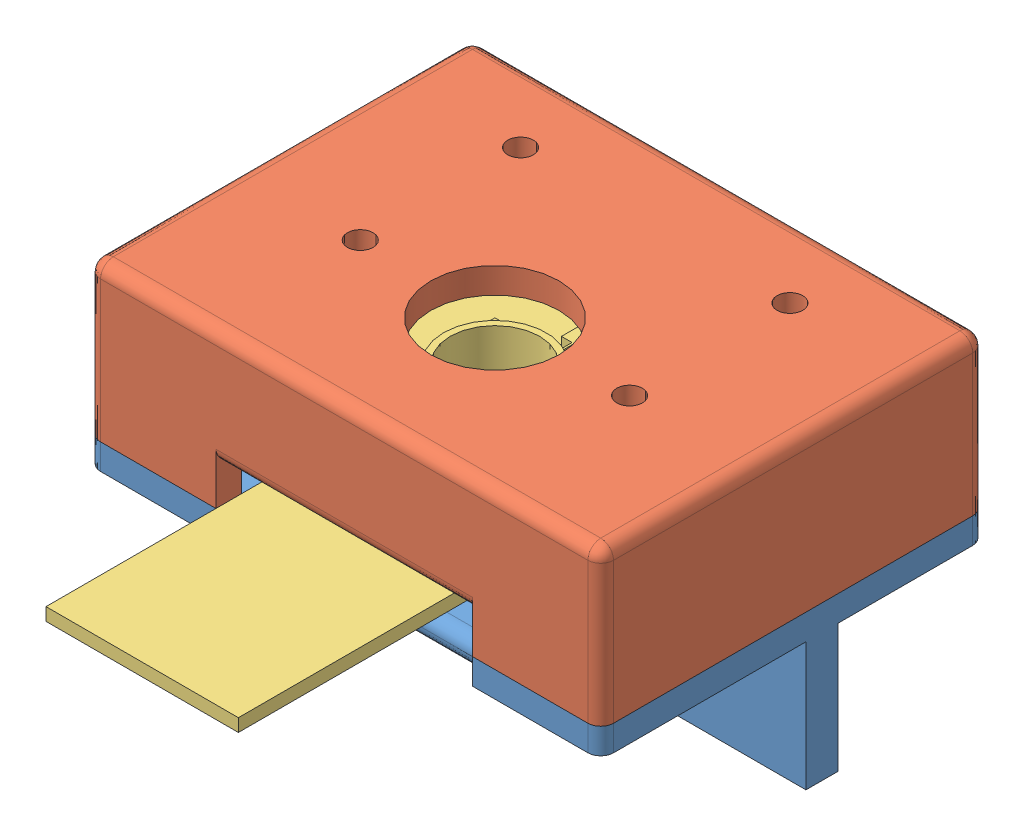
SolidWorks assembly Cam hosuing Assembly, configuration Default. Lengths in mm.
Overall size (40 24 45.75).
7 component instances, 4 part files, 8 mates.
Components (placement in the parent):
- Camera case bottomV3-1: Camera case bottomV3 [Default] at (8.7902 13.4979 31.0406) size (40 18 30)
- Camera Case Top-1: Camera Case Top [Default] at (8.7902 25.4979 31.0406) x (1 0 0) z (0 1 0) size (40 30 12)
- Raspberry Pi-1: Raspberry Pi [Default] at (8.7902 18.4979 31.7906) x (1 0 0) z (0 1 0) size (25 42 8)
- pan head tapping screw_am-1: pan head tapping screw_am [PHT 2-type I-D-10-S] at (-8.2098 12.0979 19.5406) x (0 1 0) z (0 0 1) size (11.4 4 4)
- pan head tapping screw_am-2: pan head tapping screw_am [PHT 2-type I-D-10-S] at (-8.2098 12.0979 42.5406) x (0 1 0) z (0 0 1) size (11.4 4 4)
- pan head tapping screw_am-3: pan head tapping screw_am [PHT 2-type I-D-10-S] at (25.7902 12.0979 19.5406) x (0 1 0) z (0 0 1) size (11.4 4 4)
- pan head tapping screw_am-4: pan head tapping screw_am [PHT 2-type I-D-10-S] at (25.7902 12.0979 42.5406) x (0 1 0) z (0 0 1) size (11.4 4 4)
Mates (geometry in assembly coordinates):
- Concentric1: concentric aligned: cylinder of Camera case bottomV3-1 through (-1.7098 21.4979 21.7906) axis (0 -1 0) radius 0.9; cylinder of Raspberry Pi-1 through (-1.7098 19.4979 21.7906) axis (0 -1 0) radius 1
- Concentric2: concentric aligned: cylinder of Camera case bottomV3-1 through (19.2902 21.4979 34.2906) axis (0 -1 0) radius 0.9; cylinder of Raspberry Pi-1 through (19.2902 19.4979 34.2906) axis (0 -1 0) radius 1
- Coincident1: coincident anti-aligned: plane of Camera case bottomV3-1 through (8.7902 18.4979 31.0406) normal (0 1 0); plane of Raspberry Pi-1 through (8.7902 18.4979 31.7906) normal (0 -1 0)
- Concentric3: concentric anti-aligned: cylinder of Camera case bottomV3-1 through (-1.7098 21.4979 21.7906) axis (0 -1 0) radius 0.9; cylinder of Camera Case Top-1 through (-1.7098 25.4979 21.7906) axis (0 1 0) radius 1
- Concentric4: concentric anti-aligned: cylinder of Camera case bottomV3-1 through (19.2902 21.4979 34.2906) axis (0 -1 0) radius 0.9; cylinder of Camera Case Top-1 through (19.2902 25.4979 34.2906) axis (0 1 0) radius 1
- Coincident2: coincident anti-aligned: plane of Camera case bottomV3-1 through (8.7902 15.4979 31.0406) normal (0 1 0); plane of Camera Case Top-1 through (8.7902 15.4979 31.0406) normal (0 -1 0)
- Concentric5: concentric anti-aligned: circle of Camera case bottomV3-1; circle of pan head tapping screw_am-1
- Coincident3: coincident anti-aligned: plane of Camera case bottomV3-1 through (8.7902 13.4979 31.0406) normal (0 -1 0); plane of pan head tapping screw_am-1 through (-10.2098 13.4979 19.5406) normal (0 1 0)
